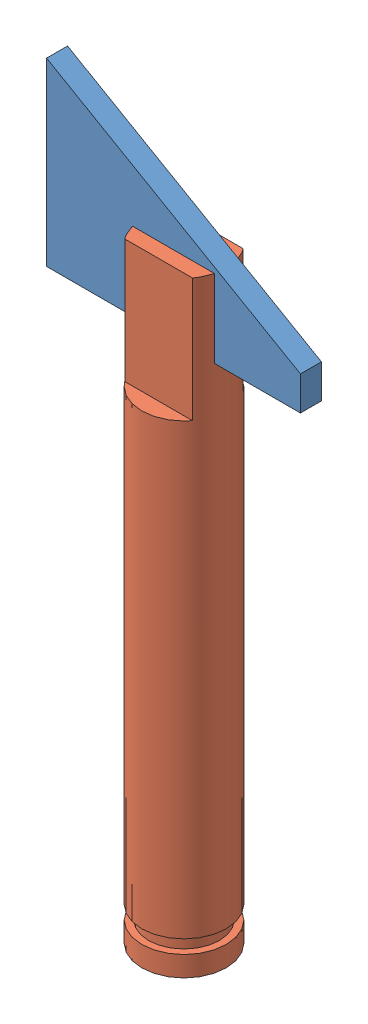
SolidWorks assembly Shaft_With_Plate_Asm, configuration Default. Lengths in mm.
Overall size (19.05 53.16 6.35).
2 component instances, 2 part files, 2 mates.
Components (placement in the parent):
- Canard_Shaft_Plate-1: Canard_Shaft_Plate [Default] at (0.1072 2.2214 -1.5658) size (19.05 13.54 1.57)
- Shaft-1: Shaft [Default] at (0.1072 -44.3876 -1.5658) x (1 0 0) z (0 1 0) size (6.35 6.35 45.47)
Mates (geometry in assembly coordinates):
- Coincident1: coincident anti-aligned: plane of Canard_Shaft_Plate-1 through (0.1072 2.2214 -1.5658) normal (0 0 1); plane of Shaft-1 through (0.1072 -44.3876 -1.5658) normal (0 0 -1)
- Coincident2: coincident: point of Canard_Shaft_Plate-1; moEndPointRef_w of Shaft-1
